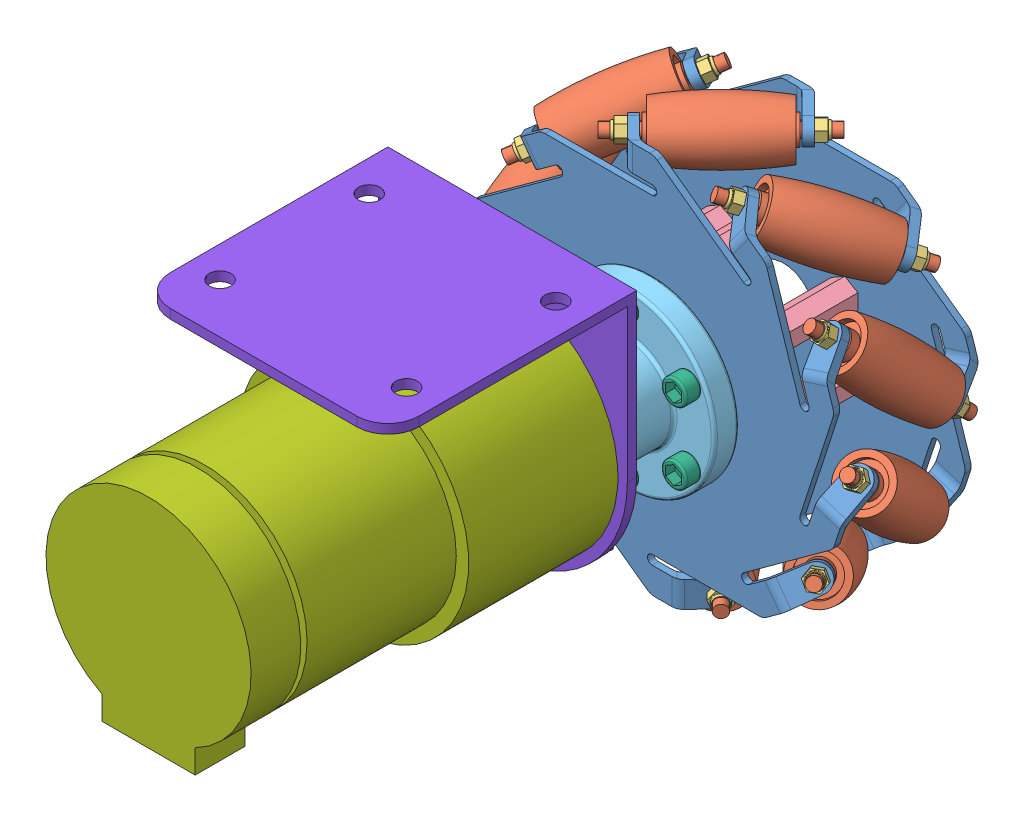
SolidWorks assembly 左后轮, configuration 默认. Lengths in mm.
Overall size (73.24 68.83 106.5).
61 component instances, 8 part files, 9 mates.
Components (placement in the parent):
- 麦克纳姆轮装配-1: 麦克纳姆轮装配 [默认] at (-17.1123 31.5894 18.4053) size (73.24 68.83 28.84)
  - 麦克纳姆轮-1: 麦克纳姆轮 [默认] at (0.4661 -9.5096 64.9154) size (62.94 61.45 5.94)
  - 麦克纳姆轮-2: 麦克纳姆轮 [默认] at (0.4661 -9.5096 44.7758) x (-1 0 0) z (0 0 -1) size (62.94 61.45 5.94)
  - 辊子-3: 辊子 [默认] at (-10.8507 19.0898 66.1624) x (0.707107 0 -0.707107) z (0.707107 0 0.707107) size (28 9.23 9.23)
  - 辊子-4: 辊子 [默认] at (-25.5101 6.9683 66.1753) x (0.572061 0.415627 -0.707107) z (-0.42304 -0.589076 -0.688496) size (28 9.23 9.23)
  - 辊子-5: 辊子 [默认] at (-30.2306 -11.4349 66.1624) x (0.218508 0.672499 -0.707107) z (0.707107 0.390255 0.589662) size (28 9.23 9.23)
  - 辊子-6: 辊子 [默认] at (-23.2364 -29.1103 66.1624) x (-0.218508 0.672499 -0.707107) z (0.108472 0.736865 0.667281) size (28 9.23 9.23)
  - 辊子-7: 辊子 [默认] at (-25.5101 -25.9875 43.5158) x (0.572061 -0.415627 0.707107) z (-0.707107 0.186947 0.681946) size (28 9.23 9.23)
  - 辊子-8: 辊子 [默认] at (-10.8636 -38.109 43.5158) x (0.707107 0 0.707107) z (0.12537 -0.984157 -0.12537) size (28 9.23 9.23)
  - 辊子-9: 辊子 [默认] at (8.1104 -39.3064 43.5158) x (0.572061 0.415627 0.707107) z (-0.707107 -0.186947 0.681946) size (28 9.23 9.23)
  - 辊子-10: 辊子 [默认] at (24.1647 -29.1225 43.5158) x (0.218508 0.672499 0.707107) z (-0.707107 -0.390255 0.589662) size (28 9.23 9.23)
  - 辊子-11: 辊子 [默认] at (8.1209 20.2797 66.1624) x (0.572061 -0.415627 -0.707107) z (0.707107 -0.186947 0.681946) size (28 9.23 9.23)
  - 辊子-12: 辊子 [默认] at (31.1668 -11.4472 43.5158) x (-0.218508 0.672499 0.707107) z (-0.805898 -0.532961 0.25784) size (28 9.23 9.23)
  - M2【螺母】-1: M2【螺母】 [默认] at (-9.3907 18.6798 46.2506) x (0.808299 -0.139279 0.572061) z (-0.572061 -0.415627 0.707107) size (2.79 3.22 1.95)
  - M2【螺母】-2: M2【螺母】 [默认] at (9.0611 19.0898 46.2506) x (0.707107 0 0.707107) z (-0.707107 0 0.707107) size (2.79 3.22 1.95)
  - M2【螺母】-3: M2【螺母】 [默认] at (24.2299 8.5758 46.2506) x (0.808299 0.139279 0.572061) z (-0.572061 0.415627 0.707107) size (2.79 3.22 1.95)
  - M2【螺母】-4: M2【螺母】 [默认] at (30.3217 -8.8462 46.2506) x (0.972031 0.086079 0.218508) z (-0.218508 0.672499 0.707107) size (2.79 3.22 1.95)
  - M2【螺母】-5: M2【螺母】 [默认] at (25.0098 -26.5216 46.2506) x (0.972031 -0.086079 -0.218508) z (0.218508 0.672499 0.707107) size (2.79 3.22 1.95)
  - M2【螺母】-6: M2【螺母】 [默认] at (10.323 -37.699 46.2506) x (0.808299 -0.139279 -0.572061) z (0.572061 0.415627 0.707107) size (2.79 3.22 1.95)
  - M2【螺母】-7: M2【螺母】 [默认] at (-8.1288 -38.109 46.2506) x (0.707107 0 -0.707107) z (0.707107 0 0.707107) size (2.79 3.22 1.95)
  - M2【螺母】-8: M2【螺母】 [默认] at (-23.2976 -27.595 46.2506) x (0.808299 0.139279 -0.572061) z (0.572061 -0.415627 0.707107) size (2.79 3.22 1.95)
  - M2【螺母】-9: M2【螺母】 [默认] at (-29.3895 -10.173 46.2506) x (0.972031 0.086079 -0.218508) z (0.218508 -0.672499 0.707107) size (2.79 3.22 1.95)
  - M2【螺母】-10: M2【螺母】 [默认] at (-24.0775 7.5024 46.2506) x (0.972031 -0.086079 0.218508) z (-0.218508 -0.672499 0.707107) size (2.79 3.22 1.95)
  - M2【螺母】-11: M2【螺母】 [默认] at (30.3217 -10.173 63.4405) x (-0.703826 -0.39331 0.591554) z (-0.218508 -0.672499 -0.707107) size (2.79 3.22 1.95)
  - M2【螺母】-13: M2【螺母】 [默认] at (25.0098 7.5024 63.4405) x (0.835211 -0.245852 0.491913) z (0.218508 -0.672499 -0.707107) size (2.79 3.22 1.95)
  - M2【螺母】-14: M2【螺母】 [默认] at (10.323 18.6798 63.4405) x (0.731274 -0.131986 0.669192) z (0.572061 -0.415627 -0.707107) size (2.79 3.22 1.95)
  - M2【螺母】-15: M2【螺母】 [默认] at (-8.1288 19.0898 63.4405) x (0.610509 -0.504536 0.610509) z (0.707107 0 -0.707107) size (2.79 3.22 1.95)
  - M2【螺母】-16: M2【螺母】 [默认] at (-23.2976 8.5758 63.4405) x (0.785961 -0.524301 0.327679) z (0.572061 0.415627 -0.707107) size (2.79 3.22 1.95)
  - M2【螺母】-17: M2【螺母】 [默认] at (-29.3895 -8.8462 63.4405) x (0.874876 -0.455982 -0.163313) z (0.218508 0.672499 -0.707107) size (2.79 3.22 1.95)
  - M2【螺母】-18: M2【螺母】 [默认] at (-24.0775 -26.5216 63.4405) x (0.829372 -0.253837 -0.497703) z (-0.218508 0.672499 -0.707107) size (2.79 3.22 1.95)
  - M2【螺母】-19: M2【螺母】 [默认] at (-9.3907 -37.699 63.4405) x (0.565426 -0.424684 -0.707062) z (-0.572061 0.415627 -0.707107) size (2.79 3.22 1.95)
  - M2【螺母】-20: M2【螺母】 [默认] at (9.0611 -38.109 63.4405) x (0.556393 -0.617133 -0.556393) z (-0.707107 0 -0.707107) size (2.79 3.22 1.95)
  - M2【螺母】-21: M2【螺母】 [默认] at (24.2299 -27.595 63.4405) x (0.779137 -0.544759 -0.310134) z (-0.572061 -0.415627 -0.707107) size (2.79 3.22 1.95)
  - 20mm长-M3【六角铜柱】-1: 20mm长-M3【六角铜柱】 [默认] at (-9.4932 -3.7596 44.9154) size (4.27 4.93 20)
  - 20mm长-M3【六角铜柱】-2: 20mm长-M3【六角铜柱】 [默认] at (-9.4932 -15.2596 44.9154) x (0.5 0.866025 0) z (0 0 1) size (4.27 4.93 20)
  - 20mm长-M3【六角铜柱】-3: 20mm长-M3【六角铜柱】 [默认] at (0.4661 -21.0096 44.9154) x (-0.5 0.866025 0) z (0 0 1) size (4.27 4.93 20)
  - 20mm长-M3【六角铜柱】-4: 20mm长-M3【六角铜柱】 [默认] at (10.4254 -15.2596 44.9154) x (-1 0 0) z (0 0 1) size (4.27 4.93 20)
  - 20mm长-M3【六角铜柱】-5: 20mm长-M3【六角铜柱】 [默认] at (10.4254 -3.7596 44.9154) x (-0.5 -0.866025 0) z (0 0 1) size (4.27 4.93 20)
  - 20mm长-M3【六角铜柱】-6: 20mm长-M3【六角铜柱】 [默认] at (0.4661 1.9904 44.9154) x (0.5 -0.866025 0) z (0 0 1) size (4.27 4.93 20)
- 法兰联轴器-1: 法兰联轴器 [默认] at (-16.6461 22.0798 84.3207) size (28 28 16)
- M3-8【内六角螺丝】-1: M3-8【内六角螺丝】 [默认] at (-6.6868 27.8298 70.1811) x (1 0 0) z (0 0 -1) size (4 4 10.5)
- M3-8【内六角螺丝】-2: M3-8【内六角螺丝】 [默认] at (-6.6868 16.3298 70.1811) x (0.5 -0.866025 0) z (0 0 -1) size (4 4 10.5)
- M3-8【内六角螺丝】-3: M3-8【内六角螺丝】 [默认] at (-16.6461 10.5798 70.1811) x (-0.5 -0.866025 0) z (0 0 -1) size (4 4 10.5)
- M3-8【内六角螺丝】-4: M3-8【内六角螺丝】 [默认] at (-26.6054 16.3298 70.1811) x (-1 0 0) z (0 0 -1) size (4 4 10.5)
- M3-8【内六角螺丝】-5: M3-8【内六角螺丝】 [默认] at (-26.6054 27.8298 70.1811) x (-0.5 0.866025 0) z (0 0 -1) size (4 4 10.5)
- M3-8【内六角螺丝】-6: M3-8【内六角螺丝】 [默认] at (-16.6461 33.5798 70.1811) x (0.5 0.866025 0) z (0 0 -1) size (4 4 10.5)
- M3-8【内六角螺丝】-7: M3-8【内六角螺丝】 [默认] at (-16.6461 33.5798 80.3207) size (4 4 10.5)
- M3-8【内六角螺丝】-8: M3-8【内六角螺丝】 [默认] at (-26.6054 27.8298 80.3207) x (0.5 0.866025 0) z (0 0 1) size (4 4 10.5)
- M3-8【内六角螺丝】-9: M3-8【内六角螺丝】 [默认] at (-26.6054 16.3298 80.3207) x (-0.5 0.866025 0) z (0 0 1) size (4 4 10.5)
- M3-8【内六角螺丝】-10: M3-8【内六角螺丝】 [默认] at (-16.6461 10.5798 80.3207) x (-1 0 0) z (0 0 1) size (4 4 10.5)
- M3-8【内六角螺丝】-11: M3-8【内六角螺丝】 [默认] at (-6.6868 16.3298 80.3207) x (-0.5 -0.866025 0) z (0 0 1) size (4 4 10.5)
- M3-8【内六角螺丝】-12: M3-8【内六角螺丝】 [默认] at (-6.6868 27.8298 80.3207) x (0.5 -0.866025 0) z (0 0 1) size (4 4 10.5)
- 电机总装-1: 电机总装 [默认] at (47.4826 107.4431 -71.3943) size (40 46 75)
  - 减速比1：10【码盘减速电机】-1: 减速比1：10【码盘减速电机】 [默认] at (-64.1287 -78.3632 203.7151) x (1 0 0) z (0 0 -1) size (37 37 75)
  - 电机支架-2: 电机支架 [默认] at (-64.1287 -78.3632 179.7151) x (1 0 0) z (0 0 -1) size (40 46 40)
  - M3-8【内六角螺丝】-13: M3-8【内六角螺丝】 [默认] at (-56.3787 -64.9398 186.2151) x (-1 0 0) z (0 0 -1) size (4 4 10.5)
  - M3-8【内六角螺丝】-14: M3-8【内六角螺丝】 [默认] at (-71.8787 -64.9398 186.2151) x (-0.5 -0.866025 0) z (0 0 -1) size (4 4 10.5)
  - M3-8【内六角螺丝】-15: M3-8【内六角螺丝】 [默认] at (-79.6287 -78.3632 186.2151) x (0.5 -0.866025 0) z (0 0 -1) size (4 4 10.5)
  - M3-8【内六角螺丝】-16: M3-8【内六角螺丝】 [默认] at (-71.8787 -91.7866 186.2151) x (1 0 0) z (0 0 -1) size (4 4 10.5)
  - M3-8【内六角螺丝】-17: M3-8【内六角螺丝】 [默认] at (-56.3787 -91.7866 186.2151) x (0.5 0.866025 0) z (0 0 -1) size (4 4 10.5)
  - M3-8【内六角螺丝】-18: M3-8【内六角螺丝】 [默认] at (-48.6287 -78.3632 186.2151) x (-0.5 0.866025 0) z (0 0 -1) size (4 4 10.5)
Mates (geometry in assembly coordinates):
- 同心1: concentric: cylinder of assembly; cylinder of assembly; cylinder of 麦克纳姆轮装配-1/麦克纳姆轮-1 through (-16.6461 33.5798 83.3207) axis (0 0 1) radius 1.5; cylinder of 法兰联轴器-1 through (-16.6461 33.5798 88.3207) axis (0 0 -1) radius 1.5
- 同心2: concentric: cylinder of assembly; cylinder of assembly; cylinder of 麦克纳姆轮装配-1/麦克纳姆轮-1 through (-16.6461 10.5798 83.3207) axis (0 0 1) radius 1.5; cylinder of 法兰联轴器-1 through (-16.6461 10.5798 88.3207) axis (0 0 -1) radius 1.5
- 重合1: coincident: plane of assembly; plane of assembly; plane of 麦克纳姆轮装配-1/麦克纳姆轮-1 through (-16.6461 47.8298 84.3207) normal (0 0 1); plane of 法兰联轴器-1 through (-16.6461 22.0798 84.3207) normal (0 0 -1)
- 同心3: concentric: cylinder of assembly; cylinder of assembly; cylinder of 麦克纳姆轮装配-1/麦克纳姆轮-2 through (-6.6868 27.8298 63.1811) axis (0 0 -1) radius 1.5; cylinder of M3-8【内六角螺丝】-1 through (-6.6868 27.8298 62.1811) axis (0 0 1) radius 1.5
- 重合2: coincident: plane of assembly; plane of assembly; plane of 麦克纳姆轮装配-1/麦克纳姆轮-2 through (-16.6461 47.8298 62.1811) normal (0 0 -1); plane of M3-8【内六角螺丝】-1 through (-6.6868 27.8298 62.1811) normal (0 0 1)
- 同心4: concentric: cylinder of assembly; cylinder of assembly; cylinder of 法兰联轴器-1 through (-16.6461 33.5798 88.3207) axis (0 0 -1) radius 1.5; cylinder of M3-8【内六角螺丝】-7 through (-16.6461 33.5798 88.3207) axis (0 0 -1) radius 1.5
- 重合3: coincident: plane of assembly; plane of assembly; plane of 法兰联轴器-1 through (-16.6461 22.0798 88.3207) normal (0 0 1); plane of M3-8【内六角螺丝】-7 through (-16.6461 33.5798 88.3207) normal (0 0 -1)
- 同心5: concentric: cylinder of 法兰联轴器-1 through (-16.6461 22.0798 84.3207) axis (0 0 1) radius 3; cylinder of ? through (-16.6461 22.0798 95.6198) axis (0 0 1) radius 3
- 距离1: distance = 2 mm: plane of assembly; plane of assembly; plane of 电机总装-1/减速比1：10【码盘减速电机】-1 through (-16.6461 22.0798 102.3207) normal (0 0 -1); plane of 法兰联轴器-1 through (-16.6461 22.0798 100.3207) normal (0 0 1)
